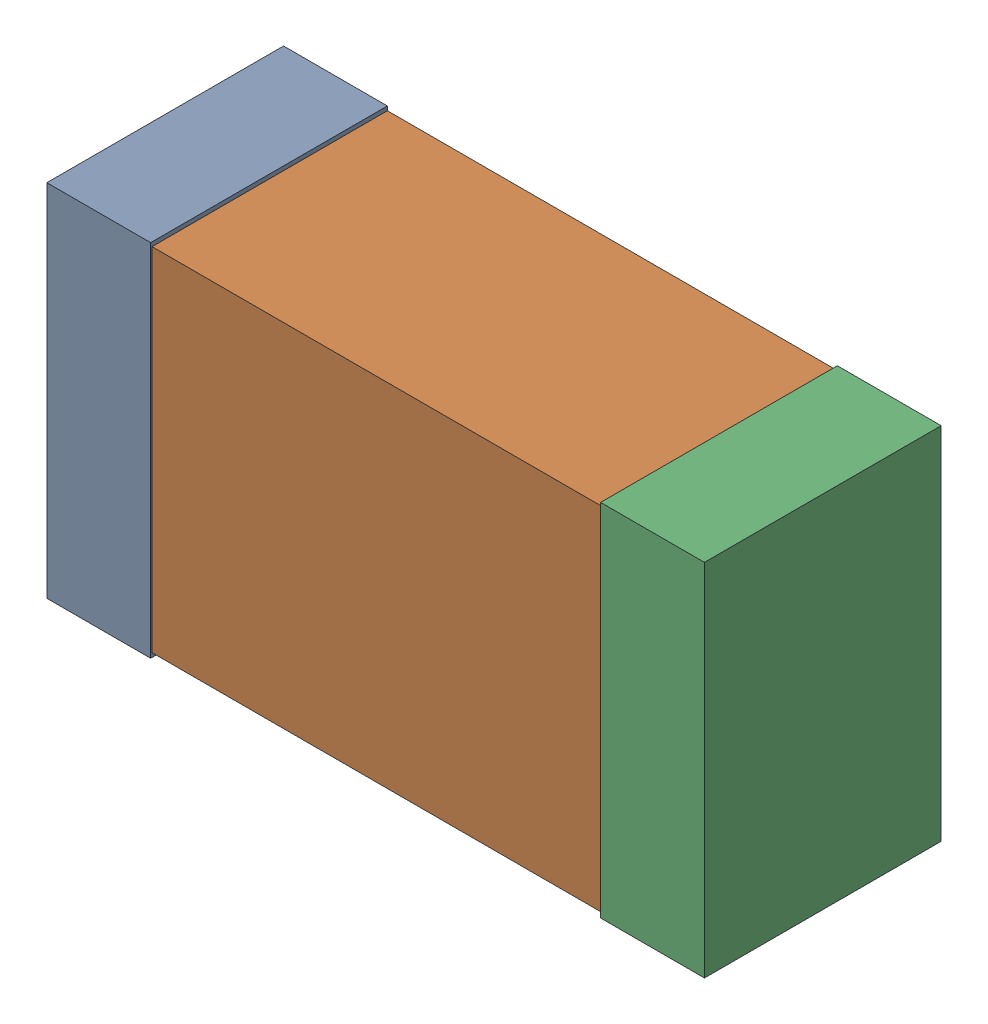
SolidWorks assembly USB01_C9, configuration Default. Lengths in mm.
Overall size (2.38 1.3 0.85).
6 component instances, 2 part files, 0 mates.
Components (placement in the parent):
- 384311232-1: 384311232 [Default] at (148.86 76.835 0) size (0.38 1.3 0.85)
  - Extruded_8-1: Extruded_8 [Default] at origin size (0.38 1.3 0.85)
- 384311360-1: 384311360 [Default] at (149.86 76.835 0) size (2.2 1.27 0.85)
  - Extruded_9-1: Extruded_9 [Default] at origin size (2.2 1.27 0.85)
- 384311232-2: 384311232 [Default] at (150.86 76.835 0) size (0.38 1.3 0.85)
  - Extruded_8-1: Extruded_8 [Default] at origin size (0.38 1.3 0.85)
